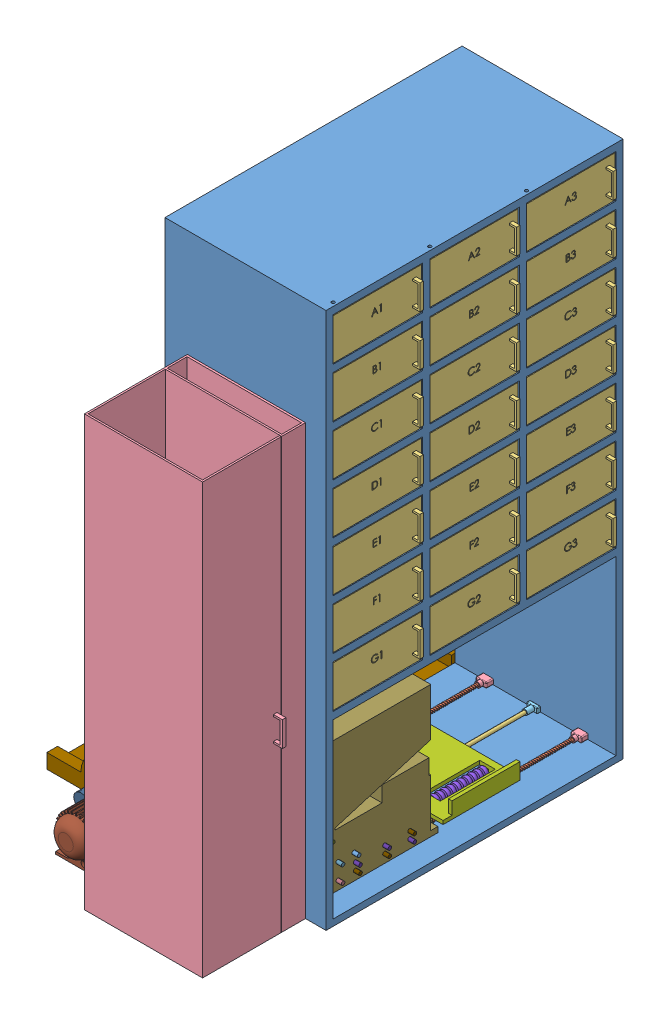
SolidWorks assembly final printer assembly, configuration Default. Lengths in mm.
Overall size (800.03 1500 1117.46).
135 component instances, 29 part files, 60 mates.
Components (placement in the parent):
- new final assembly-1: new final assembly [Default] at (673.15 179.286 -482.618) size (470.03 1500 830)
  - storage_frame-1: storage_frame [Default] at (-177.8301 428.9842 1746.1923) x (0 0 -1) z (1 0 0) size (830 1500 450)
  - pivot mentese-1: pivot mentese [Varsayılan] at (37.1699 1388.9842 1996.1923) size (13 32 13)
  - pivot mentese-2: pivot mentese [Varsayılan] at (37.1699 1308.9842 1996.1923) x (-0.999929 0 -0.011876) z (-0.011876 0 0.999929) size (13 32 13)
  - door-3: door [Default] at (26.8762 1348.9842 1882.4685) x (0.999997 0 -0.002582) z (0.002582 0 0.999997) size (40 115 247.5)
  - pivot mentese-3: pivot mentese [Varsayılan] at (37.1699 1248.9842 1996.1923) size (13 32 13)
  - pivot mentese-4: pivot mentese [Varsayılan] at (37.1699 1108.9842 1996.1923) size (13 32 13)
  - pivot mentese-5: pivot mentese [Varsayılan] at (37.1699 968.9842 1996.1923) size (13 32 13)
  - pivot mentese-6: pivot mentese [Varsayılan] at (37.1699 828.9842 1996.1923) size (13 32 13)
  - pivot mentese-7: pivot mentese [Varsayılan] at (37.1699 688.9842 1996.1923) size (13 32 13)
  - pivot mentese-8: pivot mentese [Varsayılan] at (37.1699 548.9842 1996.1923) size (13 32 13)
  - pivot mentese-9: pivot mentese [Varsayılan] at (37.1699 1168.9842 1996.1923) x (-0.999929 0 -0.011876) z (-0.011876 0 0.999929) size (13 32 13)
  - pivot mentese-10: pivot mentese [Varsayılan] at (37.1699 1028.9842 1996.1923) x (-0.999929 0 -0.011876) z (-0.011876 0 0.999929) size (13 32 13)
  - pivot mentese-11: pivot mentese [Varsayılan] at (37.1699 888.9842 1996.1923) x (-0.999929 0 -0.011876) z (-0.011876 0 0.999929) size (13 32 13)
  - pivot mentese-12: pivot mentese [Varsayılan] at (37.1699 748.9842 1996.1923) x (-0.999929 0 -0.011876) z (-0.011876 0 0.999929) size (13 32 13)
  - pivot mentese-13: pivot mentese [Varsayılan] at (37.1699 608.9842 1996.1923) x (-0.999929 0 -0.011876) z (-0.011876 0 0.999929) size (13 32 13)
  - pivot mentese-14: pivot mentese [Varsayılan] at (37.1699 468.9842 1996.1923) x (-0.999929 0 -0.011876) z (-0.011876 0 0.999929) size (13 32 13)
  - door-4: door [Default] at (26.8762 1208.9842 1882.4685) x (0.999997 0 -0.002582) z (0.002582 0 0.999997) size (40 115 247.5)
  - door-5: door [Default] at (26.8762 1068.9842 1882.4685) x (0.999997 0 -0.002582) z (0.002582 0 0.999997) size (40 115 247.5)
  - door-6: door [Default] at (26.8762 928.9842 1882.4685) x (0.999997 0 -0.002582) z (0.002582 0 0.999997) size (40 115 247.5)
  - door-7: door [Default] at (26.8762 788.9842 1882.4685) x (0.999997 0 -0.002582) z (0.002582 0 0.999997) size (40 115 247.5)
  - door-8: door [Default] at (26.8762 648.9842 1882.4685) x (0.999997 0 -0.002582) z (0.002582 0 0.999997) size (40 115 247.5)
  - door-9: door [Default] at (26.8762 508.9842 1882.4685) x (0.999997 0 -0.002582) z (0.002582 0 0.999997) size (40 115 247.5)
  - pivot mentese-15: pivot mentese [Varsayılan] at (37.1699 1388.9842 1726.1923) size (13 32 13)
  - pivot mentese-16: pivot mentese [Varsayılan] at (37.1699 1388.9842 1456.1923) size (13 32 13)
  - pivot mentese-17: pivot mentese [Varsayılan] at (37.1699 1308.9842 1726.1923) x (-0.999929 0 -0.011876) z (-0.011876 0 0.999929) size (13 32 13)
  - pivot mentese-18: pivot mentese [Varsayılan] at (37.1699 1308.9842 1456.1923) x (-0.999929 0 -0.011876) z (-0.011876 0 0.999929) size (13 32 13)
  - door-10: door [Default] at (26.8762 1348.9842 1612.4685) x (0.999997 0 -0.002582) z (0.002582 0 0.999997) size (40 115 247.5)
  - door-11: door [Default] at (26.8762 1348.9842 1342.4685) x (0.999997 0 -0.002582) z (0.002582 0 0.999997) size (40 115 247.5)
  - pivot mentese-19: pivot mentese [Varsayılan] at (37.1699 1248.9842 1726.1923) size (13 32 13)
  - pivot mentese-20: pivot mentese [Varsayılan] at (37.1699 1248.9842 1456.1923) size (13 32 13)
  - pivot mentese-21: pivot mentese [Varsayılan] at (37.1699 1108.9842 1726.1923) size (13 32 13)
  - pivot mentese-22: pivot mentese [Varsayılan] at (37.1699 1108.9842 1456.1923) size (13 32 13)
  - pivot mentese-23: pivot mentese [Varsayılan] at (37.1699 968.9842 1726.1923) size (13 32 13)
  - pivot mentese-24: pivot mentese [Varsayılan] at (37.1699 968.9842 1456.1923) size (13 32 13)
  - pivot mentese-25: pivot mentese [Varsayılan] at (37.1699 828.9842 1726.1923) size (13 32 13)
  - pivot mentese-26: pivot mentese [Varsayılan] at (37.1699 828.9842 1456.1923) size (13 32 13)
  - pivot mentese-27: pivot mentese [Varsayılan] at (37.1699 688.9842 1726.1923) size (13 32 13)
  - pivot mentese-28: pivot mentese [Varsayılan] at (37.1699 688.9842 1456.1923) size (13 32 13)
  - pivot mentese-29: pivot mentese [Varsayılan] at (37.1699 548.9842 1726.1923) size (13 32 13)
  - pivot mentese-30: pivot mentese [Varsayılan] at (37.1699 548.9842 1456.1923) size (13 32 13)
  - pivot mentese-31: pivot mentese [Varsayılan] at (37.1699 1168.9842 1726.1923) x (-0.999929 0 -0.011876) z (-0.011876 0 0.999929) size (13 32 13)
  - pivot mentese-32: pivot mentese [Varsayılan] at (37.1699 1168.9842 1456.1923) x (-0.999929 0 -0.011876) z (-0.011876 0 0.999929) size (13 32 13)
  - pivot mentese-33: pivot mentese [Varsayılan] at (37.1699 1028.9842 1726.1923) x (-0.999929 0 -0.011876) z (-0.011876 0 0.999929) size (13 32 13)
  - pivot mentese-34: pivot mentese [Varsayılan] at (37.1699 1028.9842 1456.1923) x (-0.999929 0 -0.011876) z (-0.011876 0 0.999929) size (13 32 13)
  - pivot mentese-35: pivot mentese [Varsayılan] at (37.1699 888.9842 1726.1923) x (-0.999929 0 -0.011876) z (-0.011876 0 0.999929) size (13 32 13)
  - pivot mentese-36: pivot mentese [Varsayılan] at (37.1699 888.9842 1456.1923) x (-0.999929 0 -0.011876) z (-0.011876 0 0.999929) size (13 32 13)
  - pivot mentese-37: pivot mentese [Varsayılan] at (37.1699 748.9842 1726.1923) x (-0.999929 0 -0.011876) z (-0.011876 0 0.999929) size (13 32 13)
  - pivot mentese-38: pivot mentese [Varsayılan] at (37.1699 748.9842 1456.1923) x (-0.999929 0 -0.011876) z (-0.011876 0 0.999929) size (13 32 13)
  - pivot mentese-39: pivot mentese [Varsayılan] at (37.1699 608.9842 1726.1923) x (-0.999929 0 -0.011876) z (-0.011876 0 0.999929) size (13 32 13)
  - pivot mentese-40: pivot mentese [Varsayılan] at (37.1699 608.9842 1456.1923) x (-0.999929 0 -0.011876) z (-0.011876 0 0.999929) size (13 32 13)
  - pivot mentese-41: pivot mentese [Varsayılan] at (37.1699 468.9842 1726.1923) x (-0.999929 0 -0.011876) z (-0.011876 0 0.999929) size (13 32 13)
  - pivot mentese-42: pivot mentese [Varsayılan] at (37.1699 468.9842 1456.1923) x (-0.999929 0 -0.011876) z (-0.011876 0 0.999929) size (13 32 13)
  - door-12: door [Default] at (26.8762 1208.9842 1612.4685) x (0.999997 0 -0.002582) z (0.002582 0 0.999997) size (40 115 247.5)
  - door-13: door [Default] at (26.8762 1208.9842 1342.4685) x (0.999997 0 -0.002582) z (0.002582 0 0.999997) size (40 115 247.5)
  - door-14: door [Default] at (26.8762 1068.9842 1612.4685) x (0.999997 0 -0.002582) z (0.002582 0 0.999997) size (40 115 247.5)
  - door-15: door [Default] at (26.8762 1068.9842 1342.4685) x (0.999997 0 -0.002582) z (0.002582 0 0.999997) size (40 115 247.5)
  - door-16: door [Default] at (26.8762 928.9842 1612.4685) x (0.999997 0 -0.002582) z (0.002582 0 0.999997) size (40 115 247.5)
  - door-17: door [Default] at (26.8762 928.9842 1342.4685) x (0.999997 0 -0.002582) z (0.002582 0 0.999997) size (40 115 247.5)
  - door-18: door [Default] at (26.8762 788.9842 1612.4685) x (0.999997 0 -0.002582) z (0.002582 0 0.999997) size (40 115 247.5)
  - door-19: door [Default] at (26.8762 788.9842 1342.4685) x (0.999997 0 -0.002582) z (0.002582 0 0.999997) size (40 115 247.5)
  - door-20: door [Default] at (26.8762 648.9842 1612.4685) x (0.999997 0 -0.002582) z (0.002582 0 0.999997) size (40 115 247.5)
  - door-21: door [Default] at (26.8762 648.9842 1342.4685) x (0.999997 0 -0.002582) z (0.002582 0 0.999997) size (40 115 247.5)
  - door-22: door [Default] at (26.8762 508.9842 1612.4685) x (0.999997 0 -0.002582) z (0.002582 0 0.999997) size (40 115 247.5)
  - door-23: door [Default] at (26.8762 508.9842 1342.4685) x (0.999997 0 -0.002582) z (0.002582 0 0.999997) size (40 115 247.5)
- final feeder-1: final feeder [Default] at (-660.0668 91.1588 1703.4271) x (0 0 -1) z (1 0 0) size (287.46 1200 365)
  - storage-1: storage [Default] at (15.6787 17.1114 1157.8867) size (287.46 1200 355)
  - final conveyer-1: final conveyer [Default] at (-72.8792 49.8238 1024.5051) x (0.906308 -0.422618 0) z (0 0 1) size (163 27 78)
    - belt-1: belt [Default] at (105.6125 109.464 103.3816) size (163 27 58)
    - roller-1: roller [Default] at (22.4539 108.1011 103.3816) size (25 25 78)
    - roller-2: roller [Default] at (158.4539 108.1011 103.3816) size (25 25 78)
  - pulley-1: pulley [Default] at (114.6787 93.8263 982.8867) x (-0.335462 -0.942054 0) z (0 0 1) size (10 10 10)
  - full assembly-1: full assembly [Default] at (138.0104 60.6588 899.2365) size (58.58 141.82 322.91)
    - final_takeup-1: final_takeup [Default] at (16.4319 -0.3871 22.7437) size (58.58 132.58 16.55)
      - frame-2: frame [Default] at (-26.879 103.0389 75.9065) x (0 -1 0) z (-1 0 0) size (112 16 58.58)
      - UCT208-24-1: UCT208-24 [Default] at (-29.7632 63.9987 84.9093) x (0 0 -1) z (0 1 0) size (15.1 28.57 127.15)
    - wheel rod-1: wheel rod [Default] at (-13.3313 63.6116 420.103) x (0 0 -1) z (0.885914 0.463849 0) size (320 9.53 9.53)
    - final_takeup-2: final_takeup [Default] at (-43.0945 -0.3871 497.4623) x (-1 0 0) z (0 0 -1) size (58.58 132.58 16.55)
      - frame-2: frame [Default] at (-26.879 103.0389 75.9065) x (0 -1 0) z (-1 0 0) size (112 16 58.58)
      - UCT208-24-1: UCT208-24 [Default] at (-29.7632 63.9987 84.9093) x (0 0 -1) z (0 1 0) size (15.1 28.57 127.15)
    - wheels-1: wheels [Default] at (-13.3313 63.6116 357.179) x (0.999834 0.018195 0) z (0 0 1) size (56.5 56.5 20)
    - wheels-2: wheels [Default] at (-13.3313 63.6116 287.179) x (0.999834 0.018195 0) z (0 0 1) size (56.5 56.5 20)
    - wheels-3: wheels [Default] at (-13.3313 63.6116 217.179) x (0.999834 0.018195 0) z (0 0 1) size (56.5 56.5 20)
    - wheels-4: wheels [Default] at (-13.3313 63.6116 147.179) x (0.999834 0.018195 0) z (0 0 1) size (56.5 56.5 20)
- final printer-1: final printer [Default] at (46.5311 54.0691 1441.1015) x (0 0 -1) z (1 0 0) size (365 368.75 355)
  - printer case-1: printer case [Default] at (85.0272 72.0996 448.7887) x (0 0 1) z (-1 0 0) size (325 368.75 365)
  - transfer roller-1: transfer roller [Default] at (-7.4728 97.0996 291.2887) x (0.116646 0.993174 0) z (0 0 1) size (20 20 355)
  - OPC drum-1: OPC drum [Default] at (-7.4728 142.0996 291.2887) x (0.24529 0.96945 0) z (0 0 1) size (70 70 355)
  - developer roller-1: developer roller [Default] at (-52.4728 173.7223 291.2887) x (0.071281 0.997456 0) z (0 0 1) size (40 40 355)
  - sponge roller-1: sponge roller [Default] at (-34.6311 209.5228 291.2887) size (40 40 355)
  - bring roller 1-1: bring roller 1 [Default] at (-57.4728 122.0996 291.2887) size (20 20 355)
  - bring roller 2-1: bring roller 2 [Default] at (-57.4728 102.0996 291.2887) size (20 20 355)
  - charging roller-2: charging roller [Default] at (37.5271 142.035 291.2887) size (20 20 355)
  - bring roller 1-2: bring roller 1 [Default] at (41.3043 116.6871 291.2887) size (20 20 355)
  - bring roller 2-2: bring roller 2 [Default] at (41.3043 96.6871 291.2887) size (20 20 355)
  - bring roller 1-3: bring roller 1 [Default] at (123.2434 116.6871 291.2887) size (20 20 355)
  - bring roller 2-3: bring roller 2 [Default] at (123.2434 96.6871 291.2887) size (20 20 355)
  - bring roller 1-4: bring roller 1 [Default] at (193.2676 96.6871 291.2887) size (20 20 355)
  - bring roller 2-4: bring roller 2 [Default] at (193.2676 116.6871 291.2887) size (20 20 355)
- thread rod-1: thread rod [Default] at (627.8199 133.6686 1163.5743) x (0.360452 0.932778 0) z (0 0 -1) size (10 10 405)
- thread rod-2: thread rod [Default] at (362.8199 133.6686 1163.5743) x (-0.886081 0.463531 0) z (0 0 -1) size (10 10 405)
- guide rod-1: guide rod [Default] at (495.3199 133.6686 743.5743) size (10 10 420)
- stepper-1: stepper [Default] at (627.8199 133.6686 733.5743) size (30 15 30)
- stepper-2: stepper [Default] at (362.8199 133.6686 733.5743) size (30 15 30)
- guide rod holder-1: guide rod holder [Default] at (495.3199 133.6686 743.5743) size (30 15 30)
- tray to thread holder-1: tray to thread holder [Default] at (495.3199 133.6686 1114.8599) size (30 22.5 20)
- tray to thread holder-2: tray to thread holder [Default] at (627.8199 133.6686 949.4465) size (30 22.5 20)
- tray to thread holder-3: tray to thread holder [Default] at (627.8199 133.6686 1119.4465) size (30 22.5 20)
- tray to thread holder-4: tray to thread holder [Default] at (495.3199 133.6686 953.8176) size (30 22.5 20)
- tray to thread holder-5: tray to thread holder [Default] at (362.8199 133.6686 1116.4626) size (30 22.5 20)
- tray to thread holder-6: tray to thread holder [Default] at (362.8199 133.6686 964.4734) size (30 22.5 20)
- tray-1: tray [Default] at (505.5395 163.5263 1139.4465) x (0 0 -1) z (1 0 0) size (215 54.93 325)
- final rollers-1: final rollers [Default] at (595.7467 147.539 1111.3215) x (0.988475 -0.151387 0) z (0 0 1) size (28 28 10)
- final rollers-21: final rollers [Default] at (595.7467 147.539 1096.3215) x (0.988475 -0.151387 0) z (0 0 1) size (28 28 10)
- final rollers-22: final rollers [Default] at (595.7467 147.539 1081.3215) x (0.988475 -0.151387 0) z (0 0 1) size (28 28 10)
- final rollers-23: final rollers [Default] at (595.7467 147.539 1066.3215) x (0.988475 -0.151387 0) z (0 0 1) size (28 28 10)
- final rollers-24: final rollers [Default] at (595.7467 147.539 1051.3215) x (0.988475 -0.151387 0) z (0 0 1) size (28 28 10)
- final rollers-25: final rollers [Default] at (595.7467 147.539 1036.3215) x (0.988475 -0.151387 0) z (0 0 1) size (28 28 10)
- final rollers-26: final rollers [Default] at (595.7467 147.539 1021.3215) x (0.988475 -0.151387 0) z (0 0 1) size (28 28 10)
- final rollers-27: final rollers [Default] at (595.7467 147.539 1006.3215) x (0.988475 -0.151387 0) z (0 0 1) size (28 28 10)
- final rollers-28: final rollers [Default] at (595.7467 147.539 991.3215) x (0.988475 -0.151387 0) z (0 0 1) size (28 28 10)
- final rollers-29: final rollers [Default] at (595.7467 147.539 976.3215) x (0.988475 -0.151387 0) z (0 0 1) size (28 28 10)
- final rollers-30: final rollers [Default] at (405.7467 147.539 1111.3215) x (0.988475 -0.151387 0) z (0 0 1) size (28 28 10)
- final rollers-31: final rollers [Default] at (405.7467 147.539 1096.3215) x (0.988475 -0.151387 0) z (0 0 1) size (28 28 10)
- final rollers-32: final rollers [Default] at (405.7467 147.539 1081.3215) x (0.988475 -0.151387 0) z (0 0 1) size (28 28 10)
- final rollers-33: final rollers [Default] at (405.7467 147.539 1066.3215) x (0.988475 -0.151387 0) z (0 0 1) size (28 28 10)
- final rollers-34: final rollers [Default] at (405.7467 147.539 1051.3215) x (0.988475 -0.151387 0) z (0 0 1) size (28 28 10)
- final rollers-35: final rollers [Default] at (405.7467 147.539 1036.3215) x (0.988475 -0.151387 0) z (0 0 1) size (28 28 10)
- final rollers-36: final rollers [Default] at (405.7467 147.539 1021.3215) x (0.988475 -0.151387 0) z (0 0 1) size (28 28 10)
- final rollers-37: final rollers [Default] at (405.7467 147.539 1006.3215) x (0.988475 -0.151387 0) z (0 0 1) size (28 28 10)
- final rollers-38: final rollers [Default] at (405.7467 147.539 991.3215) x (0.988475 -0.151387 0) z (0 0 1) size (28 28 10)
- final rollers-39: final rollers [Default] at (405.7467 147.539 976.3215) x (0.988475 -0.151387 0) z (0 0 1) size (28 28 10)
- main frame-1: main frame [Default] at (105.3199 118.2702 1128.5743) x (0 0 1) z (1 0 0) size (830 110.75 330)
- main thread-1: main thread [Default] at (105.3199 149.0172 713.5743) x (0.865895 -0.500226 0) z (0 0 1) size (40.02 46.21 900)
- Motor-1: Motor [Default] at (214.3029 176.1252 1690.4514) x (0 0 1) z (0 1 0) size (176.2 112 127.4)
Mates (geometry in assembly coordinates):
- Coincident1: coincident anti-aligned: plane of new final assembly-1/storage_frame-1 through (270.3199 628.2702 1543.5743) normal (0 0 1); plane of final feeder-1/storage-1 through (332.8199 1308.2702 1543.5743) normal (0 0 -1)
- Coincident2: coincident anti-aligned: line of new final assembly-1/storage_frame-1 through (337.8199 169.4702 1543.5743) axis (0 -1 0); line of final feeder-1/storage-1 through (337.8199 168.2702 1543.5743) axis (0 1 0)
- Coincident3: coincident anti-aligned: line of new final assembly-1/storage_frame-1 through (270.3199 108.2702 1543.5743) axis (1 0 0); line of final feeder-1/storage-1 through (662.8199 108.2702 1543.5743) axis (-1 0 0)
- Coincident10: coincident anti-aligned: plane of new final assembly-1/storage_frame-1 through (-698.6487 608.2702 1523.5743) normal (0 0 -1); plane of final printer-1/printer case-1 through (332.8199 276.1686 1523.5743) normal (0 0 1)
- Coincident11: coincident anti-aligned: plane of new final assembly-1/storage_frame-1 through (-698.6487 126.1686 1263.5743) normal (0 1 0); plane of final printer-1/printer case-1 through (495.3199 126.1686 1356.0743) normal (0 -1 0)
- Coincident12: coincident anti-aligned: line of new final assembly-1/storage_frame-1 through (652.8199 169.4702 1523.5743) axis (0 -1 0); line of final printer-1/printer case-1 through (652.8199 168.2686 1523.5743) axis (0 1 0)
- Concentric1: concentric aligned: cylinder of final printer-1/printer case-1 through (627.8199 133.6686 1158.5743) axis (0 0 1) radius 5; cylinder of thread rod-1 through (627.8199 133.6686 758.5743) axis (0 0 1) radius 5
- Coincident13: coincident anti-aligned: plane of final printer-1/printer case-1 through (495.3199 126.1686 1163.5743) normal (0 0 -1); plane of thread rod-1 through (627.8199 133.6686 1163.5743) normal (0 0 1)
- Concentric2: concentric aligned: cylinder of final printer-1/printer case-1 through (362.8199 133.6686 1158.5743) axis (0 0 1) radius 5; cylinder of thread rod-2 through (362.8199 133.6686 758.5743) axis (0 0 1) radius 5
- Coincident14: coincident anti-aligned: plane of final printer-1/printer case-1 through (495.3199 126.1686 1163.5743) normal (0 0 -1); plane of thread rod-2 through (362.8199 133.6686 1163.5743) normal (0 0 1)
- Coincident15: coincident anti-aligned: plane of final printer-1/printer case-1 through (495.3199 126.1686 1163.5743) normal (0 0 -1); plane of guide rod-1 through (495.3199 133.6686 1163.5743) normal (0 0 1)
- Concentric3: concentric anti-aligned: cylinder of final printer-1/printer case-1 through (495.3199 133.6686 1158.5743) axis (0 0 1) radius 5; cylinder of guide rod-1 through (495.3199 133.6686 1163.5743) axis (0 0 -1) radius 5
- Coincident16: coincident aligned: line of new final assembly-1/storage_frame-1 through (270.3199 126.1686 733.5743) axis (1 0 0); line of stepper-1 through (615.8199 126.1686 733.5743) axis (1 0 0)
- Coincident17: coincident anti-aligned: plane of new final assembly-1/storage_frame-1 through (-698.6487 126.1686 1263.5743) normal (0 1 0); plane of stepper-1 through (612.8199 126.1686 753.5743) normal (0 -1 0)
- Concentric4: concentric anti-aligned: cylinder of thread rod-1 through (627.8199 133.6686 758.5743) axis (0 0 1) radius 5; cylinder of stepper-1 through (627.8199 133.6686 763.5743) axis (0 0 -1) radius 5
- Coincident18: coincident anti-aligned: plane of new final assembly-1/storage_frame-1 through (-698.6487 608.2702 733.5743) normal (0 0 1); plane of stepper-2 through (362.8199 133.6686 733.5743) normal (0 0 -1)
- Coincident19: coincident aligned: line of new final assembly-1/storage_frame-1 through (270.3199 126.1686 733.5743) axis (1 0 0); line of stepper-2 through (350.8199 126.1686 733.5743) axis (1 0 0)
- Concentric5: concentric anti-aligned: cylinder of thread rod-2 through (362.8199 133.6686 758.5743) axis (0 0 1) radius 5; cylinder of stepper-2 through (362.8199 133.6686 763.5743) axis (0 0 -1) radius 5
- Coincident20: coincident anti-aligned: plane of new final assembly-1/storage_frame-1 through (-698.6487 608.2702 733.5743) normal (0 0 1); plane of guide rod holder-1 through (495.3199 133.6686 733.5743) normal (0 0 -1)
- Coincident21: coincident anti-aligned: plane of new final assembly-1/storage_frame-1 through (-698.6487 126.1686 1263.5743) normal (0 1 0); plane of guide rod holder-1 through (510.3199 126.1686 733.5743) normal (0 -1 0)
- Concentric6: concentric aligned: cylinder of guide rod-1 through (495.3199 133.6686 1163.5743) axis (0 0 -1) radius 5; cylinder of guide rod holder-1 through (495.3199 133.6686 763.5743) axis (0 0 -1) radius 5
- Concentric7: concentric aligned: cylinder of guide rod-1 through (495.3199 133.6686 1163.5743) axis (0 0 -1) radius 5; cylinder of tray to thread holder-1 through (495.3199 133.6686 1134.8599) axis (0 0 -1) radius 5
- Concentric8: concentric aligned: cylinder of guide rod-1 through (495.3199 133.6686 1163.5743) axis (0 0 -1) radius 5; cylinder of tray to thread holder-4 through (495.3199 133.6686 973.8176) axis (0 0 -1) radius 5
- Parallel1: parallel aligned: plane of final printer-1/printer case-1 through (657.8199 141.1686 1168.5743) normal (0 1 0); plane of tray to thread holder-1 through (495.3199 148.6686 1134.8599) normal (0 1 0)
- Parallel2: parallel aligned: plane of final printer-1/printer case-1 through (657.8199 141.1686 1168.5743) normal (0 1 0); plane of tray to thread holder-4 through (495.3199 148.6686 973.8176) normal (0 1 0)
- Concentric9: concentric anti-aligned: cylinder of thread rod-1 through (627.8199 133.6686 758.5743) axis (0 0 1) radius 5; cylinder of tray to thread holder-3 through (627.8199 133.6686 1139.4465) axis (0 0 -1) radius 5
- Parallel3: parallel aligned: plane of final printer-1/printer case-1 through (657.8199 141.1686 1168.5743) normal (0 1 0); plane of tray to thread holder-3 through (627.8199 148.6686 1139.4465) normal (0 1 0)
- Parallel4: parallel aligned: plane of final printer-1/printer case-1 through (657.8199 141.1686 1168.5743) normal (0 1 0); plane of tray to thread holder-2 through (627.8199 148.6686 969.4465) normal (0 1 0)
- Concentric10: concentric anti-aligned: cylinder of thread rod-1 through (627.8199 133.6686 758.5743) axis (0 0 1) radius 5; cylinder of tray to thread holder-2 through (627.8199 133.6686 969.4465) axis (0 0 -1) radius 5
- Concentric11: concentric anti-aligned: cylinder of thread rod-2 through (362.8199 133.6686 758.5743) axis (0 0 1) radius 5; cylinder of tray to thread holder-5 through (362.8199 133.6686 1136.4626) axis (0 0 -1) radius 5
- Parallel5: parallel aligned: plane of final printer-1/printer case-1 through (657.8199 141.1686 1168.5743) normal (0 1 0); plane of tray to thread holder-5 through (362.8199 148.6686 1136.4626) normal (0 1 0)
- Concentric12: concentric anti-aligned: cylinder of thread rod-2 through (362.8199 133.6686 758.5743) axis (0 0 1) radius 5; cylinder of tray to thread holder-6 through (362.8199 133.6686 984.4734) axis (0 0 -1) radius 5
- Parallel6: parallel aligned: plane of final printer-1/printer case-1 through (657.8199 141.1686 1168.5743) normal (0 1 0); plane of tray to thread holder-6 through (362.8199 148.6686 984.4734) normal (0 1 0)
- Lock1: lock: unknown of tray to thread holder-1; unknown of tray to thread holder-3
- Lock2: lock: unknown of tray to thread holder-1; unknown of tray to thread holder-5
- Lock3: lock: unknown of tray to thread holder-2; unknown of tray to thread holder-4
- Parallel11: parallel aligned: plane of tray to thread holder-4 through (510.3199 133.6686 973.8176) normal (1 0 0); plane of tray to thread holder-6 through (377.8199 133.6686 984.4734) normal (1 0 0)
- Lock4: lock: unknown of tray to thread holder-2; unknown of tray to thread holder-6
- Coincident34: coincident anti-aligned: plane of tray to thread holder-3 through (627.8199 148.6686 1139.4465) normal (0 1 0); plane of tray-1 through (505.5395 148.6686 949.4465) normal (0 -1 0)
- Coincident35: coincident anti-aligned: plane of tray to thread holder-6 through (362.8199 148.6686 984.4734) normal (0 1 0); plane of tray-1 through (505.5395 148.6686 949.4465) normal (0 -1 0)
- Coincident38: coincident aligned: line of tray to thread holder-2 through (640.8199 148.6686 949.4465) axis (-1 0 0); line of tray-1 through (668.0395 148.6686 949.4465) axis (-1 0 0)
- Parallel13: parallel aligned: plane of final printer-1/printer case-1 through (657.8199 276.1686 1188.5743) normal (1 0 0); plane of tray-1 through (668.0395 163.5263 949.4465) normal (1 0 0)
- Coincident44: coincident anti-aligned: plane of tray to thread holder-2 through (642.8199 133.6686 969.4465) normal (1 0 0); plane of tray-1 through (642.8199 143.6686 1139.4465) normal (-1 0 0)
- Concentric13: concentric aligned: cylinder of tray-1 through (595.7467 147.539 1139.4465) axis (0 0 -1) radius 2.5; cylinder of final rollers-1 through (595.7467 147.539 1121.3215) axis (0 0 -1) radius 2.5
- Coincident46: coincident anti-aligned: plane of tray-1 through (617.1942 193.5938 1121.3215) normal (0 0 -1); plane of final rollers-1 through (595.7467 147.539 1121.3215) normal (0 0 1)
- Coincident47: coincident aligned: plane of tray to thread holder-3 through (627.8199 133.6686 1139.4465) normal (0 0 1); plane of tray-1 through (505.5395 163.5263 1139.4465) normal (0 0 1)
- Coincident48: coincident anti-aligned: line of new final assembly-1/storage_frame-1 through (270.3199 108.2702 713.5743) axis (0 0 1); line of ASRS_ASSEMBLY-1/main frame-1 through (270.3199 108.2702 2065.8266) axis (0 0 -1)
- Coincident50: coincident anti-aligned: plane of new final assembly-1/storage_frame-1 through (270.3199 628.2702 1543.5743) normal (-1 0 0); plane of ASRS_ASSEMBLY-1/main frame-1 through (270.3199 -171.7298 1715.3607) normal (1 0 0)
- Coincident51: coincident anti-aligned: line of new final assembly-1/storage_frame-1 through (270.3199 108.2702 713.5743) axis (0 0 1); line of ASRS_ASSEMBLY-1/mainframe own-1 through (270.3199 108.2702 2263.5743) axis (0 0 -1)
- Coincident52: coincident aligned: line of new final assembly-1/storage_frame-1 through (270.3199 1608.2702 713.5743) axis (0 -1 0); line of ASRS_ASSEMBLY-1/mainframe own-1 through (270.3199 138.2702 713.5743) axis (0 -1 0)
- Coincident53: coincident anti-aligned: plane of new final assembly-1/storage_frame-1 through (270.3199 628.2702 1543.5743) normal (-1 0 0); plane of main frame-1 through (270.3199 118.2702 713.5743) normal (1 0 0)
- Coincident54: coincident anti-aligned: line of new final assembly-1/storage_frame-1 through (270.3199 1608.2702 713.5743) axis (0 -1 0); line of main frame-1 through (270.3199 108.2702 713.5743) axis (0 1 0)
- Coincident55: coincident aligned: line of new final assembly-1/storage_frame-1 through (270.3199 108.2702 713.5743) axis (0 0 1); line of main frame-1 through (270.3199 108.2702 713.5743) axis (0 0 1)
- Concentric14: concentric anti-aligned: cylinder of main frame-1 through (105.3199 149.0172 -165.8981) axis (0 0 1) radius 20; cylinder of main thread-1 through (105.3199 149.0172 1613.5743) axis (0 0 -1) radius 20
- Coincident56: coincident aligned: plane of main frame-1 through (105.3199 118.2702 713.5743) normal (0 0 -1); plane of main thread-1 through (105.3199 149.0172 713.5743) normal (0 0 -1)
- Coincident57: coincident aligned: plane of main frame-1 through (105.3199 108.2702 1128.5743) normal (0 -1 0); plane of Motor-1 through (168.2504 141.4406 1681.2404) normal (0 -1 0)
- Parallel14: parallel aligned: cylinder of main thread-1 through (105.3199 149.0172 1613.5743) axis (0 0 -1) radius 20; cylinder of Motor-1 through (214.3199 179.6702 1684.285) axis (0 0 -1) radius 20
- Coincident58: coincident anti-aligned: plane of main thread-1 through (105.3199 149.0172 1613.5743) normal (0 0 1); plane of Motor-1 through (214.3199 228.6702 1613.5743) normal (0 0 -1)
- Parallel15: parallel aligned: cylinder of main thread-1 through (105.3199 149.0172 1613.5743) axis (0 0 -1) radius 20; cylinder of Motor-1 through (214.3199 179.6702 1684.285) axis (0 0 -1) radius 20
- Coincident59: coincident anti-aligned: plane of new final assembly-1/storage_frame-1 through (270.3199 628.2702 1543.5743) normal (-1 0 0); plane of Motor-1 through (270.3199 108.2702 1736.7743) normal (1 0 0)
